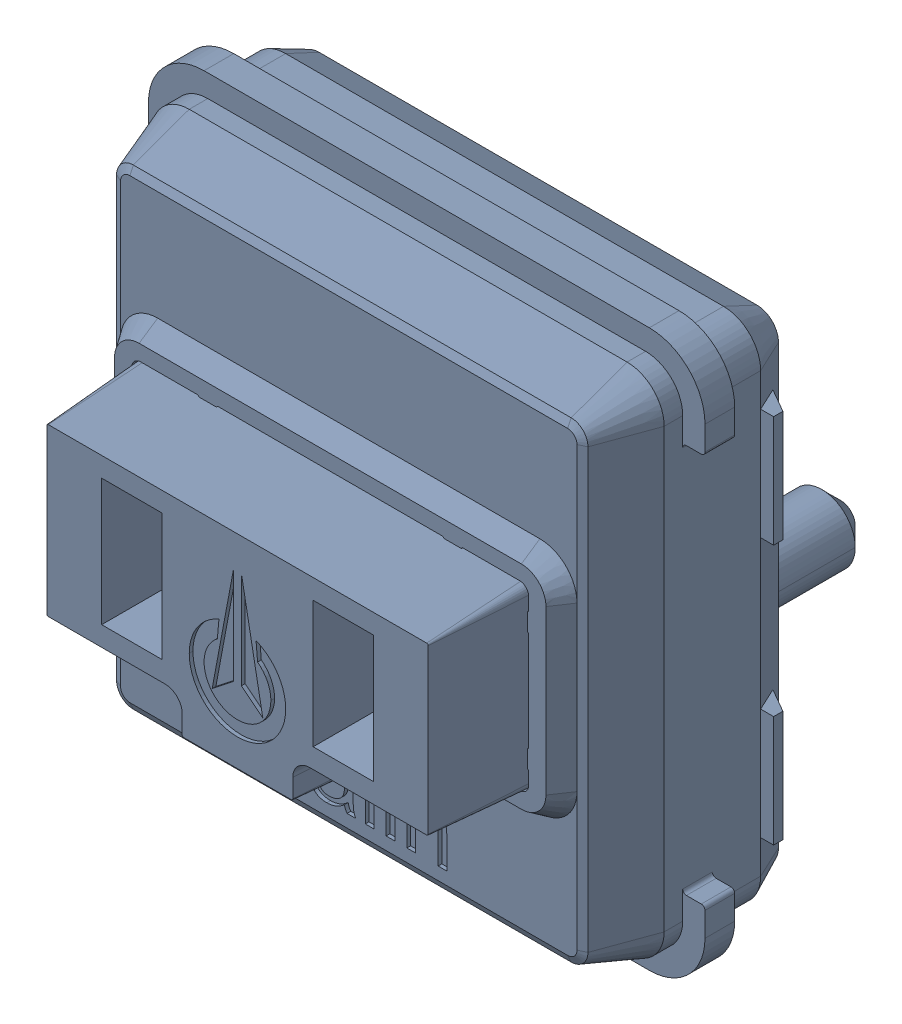
SolidWorks assembly SW5_1.step, configuration Default. Lengths in mm.
Overall size (15 15 11.1).
2 component instances, 2 part files, 0 mates.
Components (placement in the parent):
- Kailh LP Choc Burnt Orange_1.step-3: Kailh LP Choc Burnt Orange_1.step [Default] at (428.7827 226.3933 2.7) x (0 -1 0) z (-1 0 0) size (15 11.1 15)
- WS2812-2020_1.step-3: WS2812-2020_1.step [Default] at (428.8893 231.0345 0.3) x (1 0 0) z (0 -1 0) size (2.2 0.86 2)
